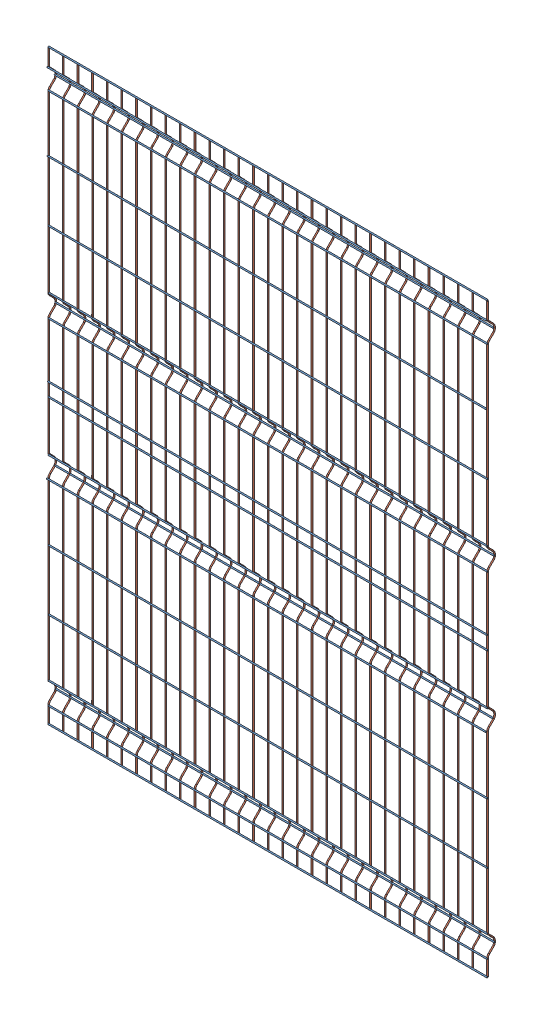
SolidWorks assembly PAINEL MALHA 50X200 MM, configuration Valor predeterminado. Lengths in mm.
Overall size (1504.23 2005.6 33.21).
21 component instances, 2 part files, 19 mates.
Components (placement in the parent):
- fios horizontais-2: fios horizontais [Valor predeterminado] at (-2521.698 640.3793 2012.8813) x (0 -1 0) z (0 0 1) size (4 1500 4)
- fios horizontais-3: fios horizontais [Valor predeterminado] at (-2519.5235 513.4266 2015.5005) x (0 0 -1) z (0 -1 0) size (4 1500 4)
- fios horizontais-4: fios horizontais [Valor predeterminado] at (-1022.4961 581.4754 2015.7657) x (0 1 0) z (0 0 1) size (4 1500 4)
- fios horizontais-5: fios horizontais [Valor predeterminado] at (-1022.6236 546.868 1990.9563) x (0 1 0) z (0 0 1) size (4 1500 4)
- fios horizontais-6: fios horizontais [Valor predeterminado] at (-1019.5235 -160.9915 2014.9987) x (0 1 0) z (0 0 1) size (4 1500 4)
- fios horizontais-7: fios horizontais [Valor predeterminado] at (-1019.5235 -86.7664 2013.9934) x (0 1 0) z (0 0 1) size (4 1500 4)
- fios horizontais-8: fios horizontais [Valor predeterminado] at (-1019.5235 -125.5109 1991.7476) x (0 1 0) z (0 0 1) size (4 1500 4)
- fios horizontais-9: fios horizontais [Valor predeterminado] at (-1019.5235 -564.9176 2015.2661) x (0 1 0) z (0 0 1) size (4 1500 4)
- fios horizontais-10: fios horizontais [Valor predeterminado] at (-1022.8503 -608.7464 1991.8339) x (0 1 0) z (0 0 1) size (4 1500 4)
- fios horizontais-11: fios horizontais [Valor predeterminado] at (-1022.5296 -635.9373 2017.3313) x (0 1 0) z (0 0 1) size (4 1500 4)
- fios horizontais-12: fios horizontais [Valor predeterminado] at (-1019.7367 -1271.0065 1989.9373) x (0 1 0) z (0 0 1) size (4 1500 4)
- fios horizontais-13: fios horizontais [Valor predeterminado] at (-1019.5235 -1233.505 2015.0466) x (0 1 0) z (0 0 1) size (4 1500 4)
- fios horizontais-14: fios horizontais [Valor predeterminado] at (-1019.5235 -1307.083 2015.6362) x (0 1 0) z (0 0 1) size (4 1500 4)
- fios horizontais-15: fios horizontais [Valor predeterminado] at (-1019.5235 -1361.216 2016.1015) x (0 1 0) z (0 0 1) size (4 1500 4)
- fios horizontais-16: fios horizontais [Valor predeterminado] at (-1019.5235 113.4064 2015.5568) x (0 1 0) z (0 0 1) size (4 1500 4)
- fios horizontais-17: fios horizontais [Valor predeterminado] at (-1023.5235 317.7131 2014.5164) x (0 1 0) z (0 0 1) size (4 1500 4)
- fios horizontais-18: fios horizontais [Valor predeterminado] at (-1019.5235 -832.4892 2015.292) x (0 1 0) z (0 0 1) size (4 1500 4)
- fios horizontais-19: fios horizontais [Valor predeterminado] at (-1019.5235 -1038.7608 2014.2024) x (0 1 0) z (0 0 1) size (4 1500 4)
- fios horizontais-20: fios horizontais [Valor predeterminado] at (-1019.5235 -347.2828 2016.9813) x (0 -0.631522 -0.775358) z (0 0.775358 -0.631522) size (4 1500 4)
- fios horizontais-21: fios horizontais [Valor predeterminado] at (-1019.5235 -393.9799 2015.1382) x (0 0 -1) z (0 1 0) size (4 1500 4)
- fio vertical corrigido-1: fio vertical corrigido [Valor predeterminado] at (-2521.5235 564.2789 3539.9329) size (1504.23 2000 28.43)
Mates (geometry in assembly coordinates):
- Tangente1: tangent aligned: plane of fios horizontais-8 through (-1019.5235 -125.5109 1991.7476) normal (1 0 0); face of fio vertical corrigido-1
- Tangente18: tangent anti-aligned: cylinder of fios horizontais-2 through (-1021.698 640.3793 2012.8813) axis (-1 0 0) radius 2; plane of fio vertical corrigido-1 through (-1021.5235 638.3793 2012.9813) normal (0 1 0)
- Tangente19: tangent aligned: plane of fios horizontais-3 through (-1019.5235 513.4267 2015.5005) normal (1 0 0); edge_curve of fio vertical corrigido-1
- Tangente20: tangent aligned: plane of fios horizontais-17 through (-2523.5235 317.7131 2014.5164) normal (-1 0 0); cylinder of fio vertical corrigido-1 through (-2521.5235 511.0013 2012.9813) axis (0 -1 0) radius 2
- Tangente21: tangent aligned: plane of fios horizontais-7 through (-1019.5235 -86.7664 2013.9934) normal (1 0 0); cylinder of fio vertical corrigido-1 through (-1021.5235 511.0013 2012.9813) axis (0 -1 0) radius 2
- Tangente22: tangent aligned: plane of fios horizontais-8 through (-1019.5235 -125.5109 1991.7476) normal (1 0 0); edge_curve of fio vertical corrigido-1
- Tangente23: tangent aligned: plane of fios horizontais-6 through (-1019.5235 -160.9915 2014.9987) normal (1 0 0); edge_curve of fio vertical corrigido-1
- Tangente24: tangent aligned: plane of fios horizontais-16 through (-1019.5235 113.4064 2015.5568) normal (1 0 0); cylinder of fio vertical corrigido-1 through (-1021.5235 511.0013 2012.9813) axis (0 -1 0) radius 2
- Tangente25: tangent aligned: plane of fios horizontais-20 through (-1019.5235 -347.2828 2016.9813) normal (1 0 0); cylinder of fio vertical corrigido-1 through (-1021.5235 -161.2153 2012.9813) axis (0 -1 0) radius 2
- Tangente26: tangent aligned: plane of fios horizontais-21 through (-1019.5235 -393.9799 2015.1382) normal (1 0 0); cylinder of fio vertical corrigido-1 through (-1021.5235 -161.2153 2012.9813) axis (0 -1 0) radius 2
- Tangente27: tangent anti-aligned: cylinder of fios horizontais-20 through (-2519.5235 -347.2828 2016.9813) axis (1 0 0) radius 2; cylinder of fio vertical corrigido-1 through (-1021.5235 -161.2153 2012.9813) axis (0 -1 0) radius 2
- Tangente28: tangent aligned: plane of fios horizontais-9 through (-1019.5235 -564.9176 2015.2661) normal (1 0 0); cylinder of fio vertical corrigido-1 through (-1021.5235 -161.2153 2012.9813) axis (0 -1 0) radius 2
- Tangente32: tangent aligned: cylinder of fios horizontais-10 through (-2522.8503 -608.7464 1991.8339) axis (1 0 0) radius 2; edge_curve of fio vertical corrigido-1
- Tangente33: tangent aligned: plane of fios horizontais-18 through (-1019.5235 -832.4892 2015.292) normal (1 0 0); cylinder of fio vertical corrigido-1 through (-1021.5235 -633.4319 2012.9813) axis (0 -1 0) radius 2
- Tangente35: tangent aligned: plane of fios horizontais-19 through (-1019.5235 -1038.7608 2014.2024) normal (1 0 0); cylinder of fio vertical corrigido-1 through (-1021.5235 -633.4319 2012.9813) axis (0 -1 0) radius 2
- Tangente36: tangent aligned: plane of fios horizontais-15 through (-1019.5235 -1361.216 2016.1015) normal (1 0 0); cylinder of fio vertical corrigido-1 through (-1021.5235 -1304.6485 2012.9813) axis (0 -1 0) radius 2
- Tangente37: tangent aligned: plane of fios horizontais-14 through (-1019.5235 -1307.083 2015.6362) normal (1 0 0); cylinder of fio vertical corrigido-1 through (-1021.5235 -1304.6485 2012.9813) axis (0 -1 0) radius 2
- Tangente38: tangent: circle of fios horizontais-12; edge_curve of fio vertical corrigido-1
- Tangente39: tangent aligned: plane of fios horizontais-13 through (-1019.5235 -1233.505 2015.0466) normal (1 0 0); cylinder of fio vertical corrigido-1 through (-1021.5235 -633.4319 2012.9813) axis (0 -1 0) radius 2
